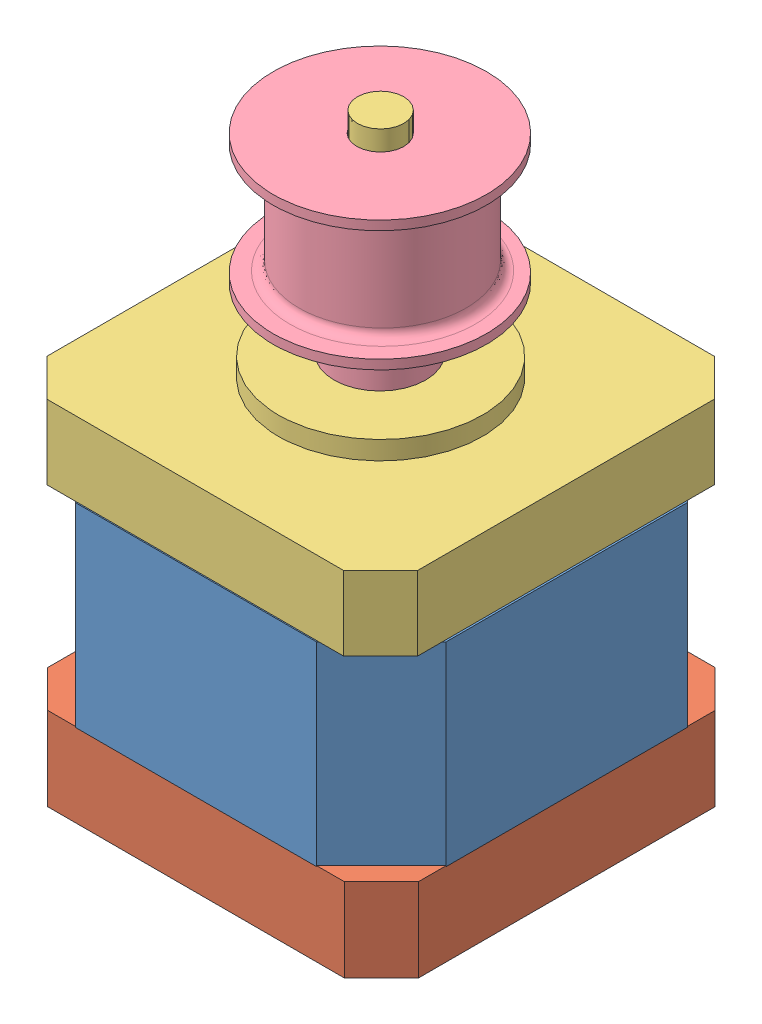
SolidWorks assembly motor, configuration Default. Lengths in mm.
Overall size (42.09 63.03 42.01).
4 component instances, 4 part files, 0 mates.
Components (placement in the parent):
- middle-1: middle [Default] at (-5.5346 -7.2158 0.6893) size (42 21 42)
- bottom-1: bottom [Default] at (-5.5376 -16.1296 0.6793) size (42 9 42)
- upper-1: upper [Default] at (-5.6243 13.9005 0.6796) size (42 33 42)
- motor_gear-1: motor_gear [Default] at (-5.6782 24.141 0.7046) size (23 20.6 23)
